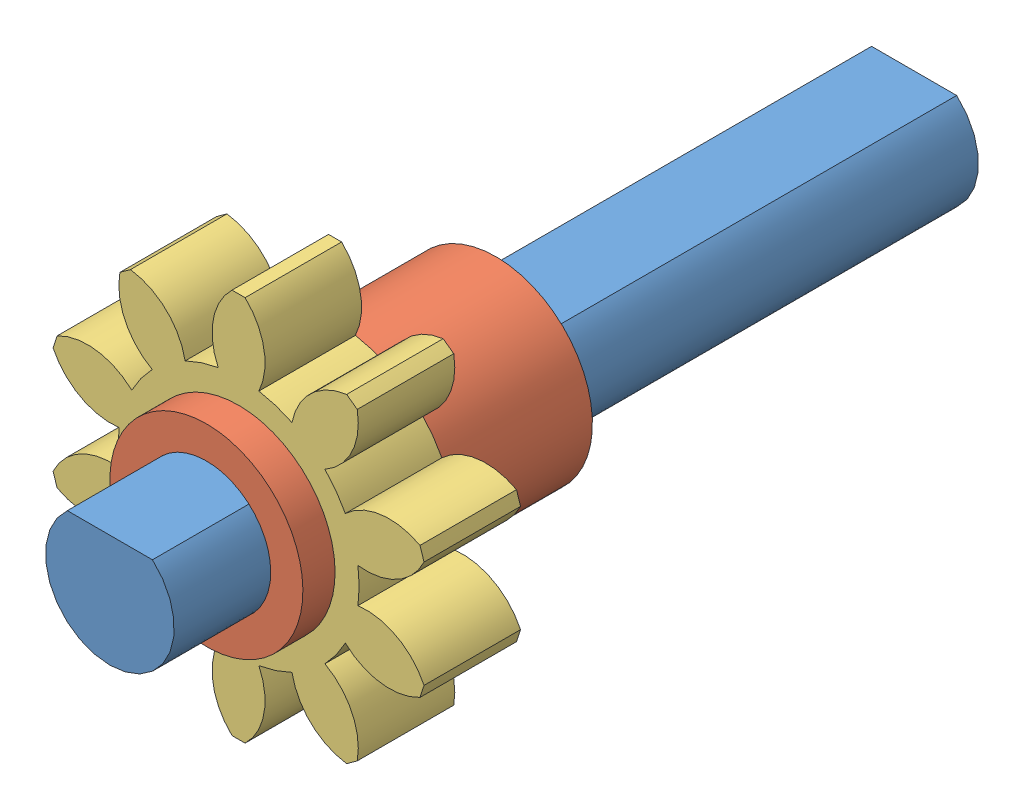
SolidWorks assembly subassem1, configuration Default. Lengths in mm.
Overall size (11.53 12 25).
4 component instances, 3 part files, 7 mates.
Components (placement in the parent):
- axle-1: axle [Long] at (0.4719 6.9883 7.4595) size (4 3.5 25)
- spacer-1: spacer [1mm Tall] at (0.4719 6.9883 28.4595) x (0.18763 0.98224 0) z (0 0 1) size (6 6 1)
- spacer-2: spacer [5mm Tall] at (0.4719 6.9883 20.4595) x (-0.596298 -0.802763 0) z (0 0 1) size (6 6 5)
- root_gear-1: root_gear [10T 1.0Mod] at (0.4719 6.9883 25.4595) size (11.53 12 3)
Mates (geometry in assembly coordinates):
- Concentric2: concentric aligned: cylinder of axle-1 through (0.4719 6.9883 32.4595) axis (0 0 -1) radius 2; cylinder of spacer-1 through (0.4719 6.9883 29.4595) axis (0 0 -1) radius 2
- Distance1: distance = 3 mm aligned: plane of spacer-1 through (0.4719 6.9883 29.4595) normal (0 0 1); plane of axle-1 through (0.4719 6.9883 32.4595) normal (0 0 1)
- Concentric3: concentric aligned: cylinder of axle-1 through (0.4719 6.9883 32.4595) axis (0 0 -1) radius 2; cylinder of spacer-2 through (0.4719 6.9883 25.4595) axis (0 0 -1) radius 2
- Concentric4: concentric aligned: cylinder of axle-1 through (0.4719 6.9883 32.4595) axis (0 0 -1) radius 2; cylinder of root_gear-1 through (0.4719 6.9883 35.4595) axis (0 0 -1) radius 2
- Coincident3: coincident anti-aligned: plane of axle-1 through (-0.8509 8.4883 32.4595) normal (0 1 0); plane of root_gear-1 through (1.7948 8.4883 35.4595) normal (0 -1 0)
- Coincident7: coincident anti-aligned: plane of spacer-1 through (0.4719 6.9883 28.4595) normal (0 0 -1); plane of root_gear-1 through (0.4719 6.9883 28.4595) normal (0 0 1)
- Coincident8: coincident anti-aligned: circle of spacer-2; plane of root_gear-1 through (0.4719 6.9883 25.4595) normal (0 0 -1)
